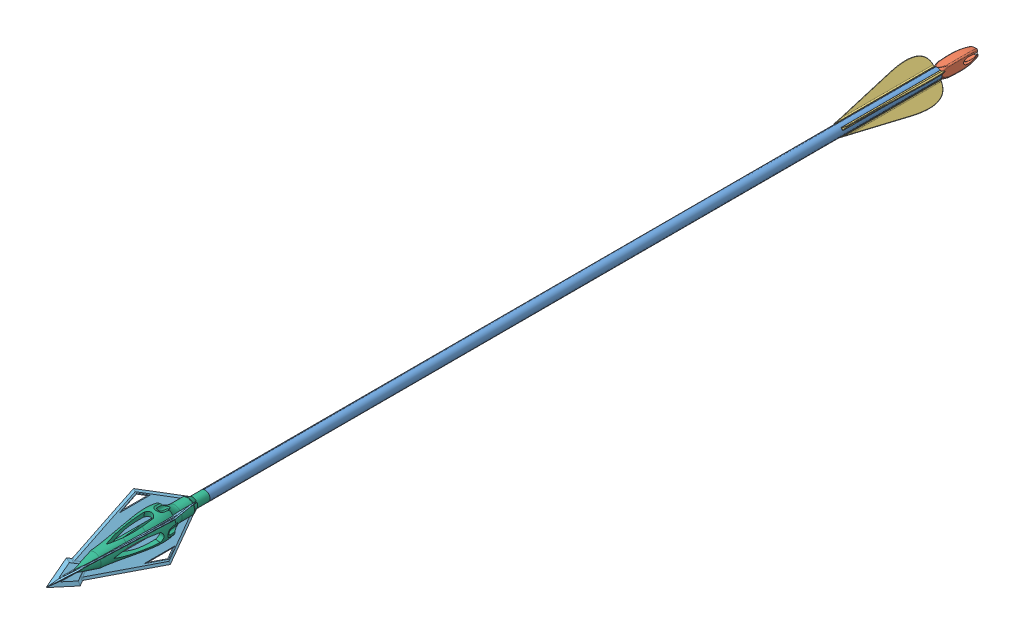
SolidWorks assembly Arrow^Main Assembly, configuration Default. Lengths in mm.
Overall size (67.86 67.86 748.25).
9 component instances, 6 part files, 13 mates.
Components (placement in the parent):
- Part31 (Victoria)-1: Part31 (Victoria) [Default] at (208.1597 284.3974 488.3999) size (8 8 600)
- Part 32-1: Part 32 [Default] at (208.1597 284.3974 181.3999) x (0 0 -1) z (0.994804 0.101805 0) size (30 11.02 10.94)
- Part33 (Victoria)-1: Part33 (Victoria) [Default] at (210.8443 280.9454 198.3999) x (0 0 -1) z (-0.789379 -0.613906 0) size (82.15 14.3 2.99)
- Part 34-1: Part 34 [Default] at (208.1597 284.3974 767.3999) x (-0.939334 0.343003 0) z (0.343003 0.939334 0) size (7 21 7)
- Part35 (Victoria)-1: Part35 (Victoria) [Default] at (208.3579 284.5515 878.6499) x (0 0 -1) z (0.613906 -0.789379 0) size (118 48.36 48.36)
- Part 36-1: Part 36 [Default] at (208.1597 284.3974 778.6499) x (0.992272 -0.124078 0) z (0 0 -1) size (23.3 23.3 120)
- Part33 (Victoria)-5: Part33 (Victoria) [Default] at (204.7077 281.7128 198.3999) x (0 0 -1) z (-0.613906 0.789379 0) size (82.15 14.3 2.99)
- Part33 (Victoria)-6: Part33 (Victoria) [Default] at (205.4751 287.8493 198.3999) x (0 0 -1) z (0.789379 0.613906 0) size (82.15 14.3 2.99)
- Part33 (Victoria)-7: Part33 (Victoria) [Default] at (211.6116 287.082 198.3999) x (0 0 -1) z (0.613906 -0.789379 0) size (82.15 14.3 2.99)
Mates (geometry in assembly coordinates):
- Concentric1: concentric anti-aligned: circle of Part31 (Victoria)-1; circle of Part 32-1
- Coincident1: coincident anti-aligned: plane of Part31 (Victoria)-1 through (208.1597 284.3974 188.3999) normal (0 0 -1); plane of Part 32-1 through (208.1597 284.3974 188.3999) normal (0 0 1)
- Concentric2: concentric aligned: cylinder of Part31 (Victoria)-1 through (208.1597 284.3974 788.3999) axis (0 0 -1) radius 4; cylinder of Part33 (Victoria)-1 through (208.1597 284.3974 278.3999) axis (0 0 -1) radius 4
- Coincident5: coincident: point of Part 32-1; circle of Part33 (Victoria)-1
- Concentric4: concentric anti-aligned: circle of Part31 (Victoria)-1; circle of Part 34-1
- Concentric5: concentric aligned: cylinder of Part 34-1 through (208.1597 284.3974 767.3999) axis (0 0 -1) radius 1.25; cylinder of Part 36-1 through (208.1597 284.3974 778.6499) axis (0 0 -1) radius 1.5
- Coincident7: coincident anti-aligned: plane of Part31 (Victoria)-1 through (208.1597 284.3974 788.3999) normal (0 0 1); circle of Part 34-1
- Concentric6: concentric aligned: cylinder of Part 34-1 through (208.1597 284.3974 767.3999) axis (0 0 -1) radius 3; cylinder of Part 36-1 through (208.1597 284.3974 778.6499) axis (0 0 -1) radius 4
- Coincident8: coincident anti-aligned: plane of Part31 (Victoria)-1 through (208.1597 284.3974 788.3999) normal (0 0 1); plane of Part 36-1 through (212.1288 283.9011 788.3999) normal (0 0 -1)
- Coincident12: coincident anti-aligned: plane of Part35 (Victoria)-1 through (208.4002 284.9026 878.6499) normal (0.789379 0.613906 0); plane of Part 36-1 through (206.0987 287.8618 898.6499) normal (-0.789379 -0.613906 0)
- Coincident13: coincident anti-aligned: plane of Part35 (Victoria)-1 through (208.0509 284.9462 878.6499) normal (-0.613906 0.789379 0); plane of Part 36-1 through (211.0102 287.2477 898.6499) normal (0.613906 -0.789379 0)
- Coincident14: coincident: line of Part35 (Victoria)-1 through (208.1597 284.3974 898.6499) axis (-0.035719 -0.285651 -0.957668); point of Part 36-1
- Parallel1: parallel aligned: plane of Part33 (Victoria)-1 through (216.7607 272.9306 206.215) normal (-0.789379 -0.613906 0); plane of Part35 (Victoria)-1 through (207.9191 283.8922 878.6499) normal (-0.789379 -0.613906 0)
